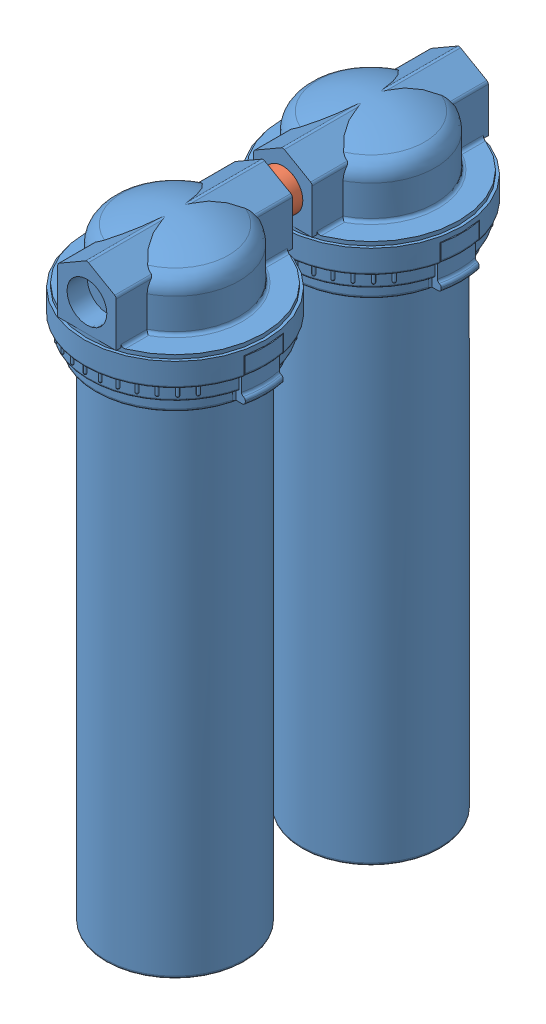
SolidWorks assembly ReadingTech_3P-150-M06-DC, configuration Default. Lengths in mm.
Overall size (121.86 436.11 252.73).
3 component instances, 2 part files, 3 mates.
Components (placement in the parent):
- ReadingTech_3P150M06F-1: ReadingTech_3P150M06F [Default] at (-59.8243 -179.3942 20.9569) size (121.86 436.11 121.67)
- ReadingTech_3P150M06F-2: ReadingTech_3P150M06F [Default] at (-59.8243 -179.3942 -110.1071) size (121.86 436.11 121.67)
- ReadingTech- 90,150cfm_connector_.75in-1: ReadingTech- 90,150cfm_connector_.75in [Default] at (-59.8243 209.6068 -37.9711) x (1 0 0) z (0 1 0) size (26.67 13.21 26.67)
Mates (geometry in assembly coordinates):
- Coincident1: coincident anti-aligned: circle of ReadingTech_3P150M06F-2; circle of ReadingTech- 90,150cfm_connector_.75in-1
- Coincident2: coincident aligned: circle of ReadingTech_3P150M06F-1; circle of ReadingTech- 90,150cfm_connector_.75in-1
- Coincident3: coincident aligned: plane of ReadingTech_3P150M06F-1 through (-40.2663 222.3068 79.8849) normal (1 0 0); plane of ReadingTech_3P150M06F-2 through (-40.2663 222.3068 -51.1791) normal (1 0 0)
